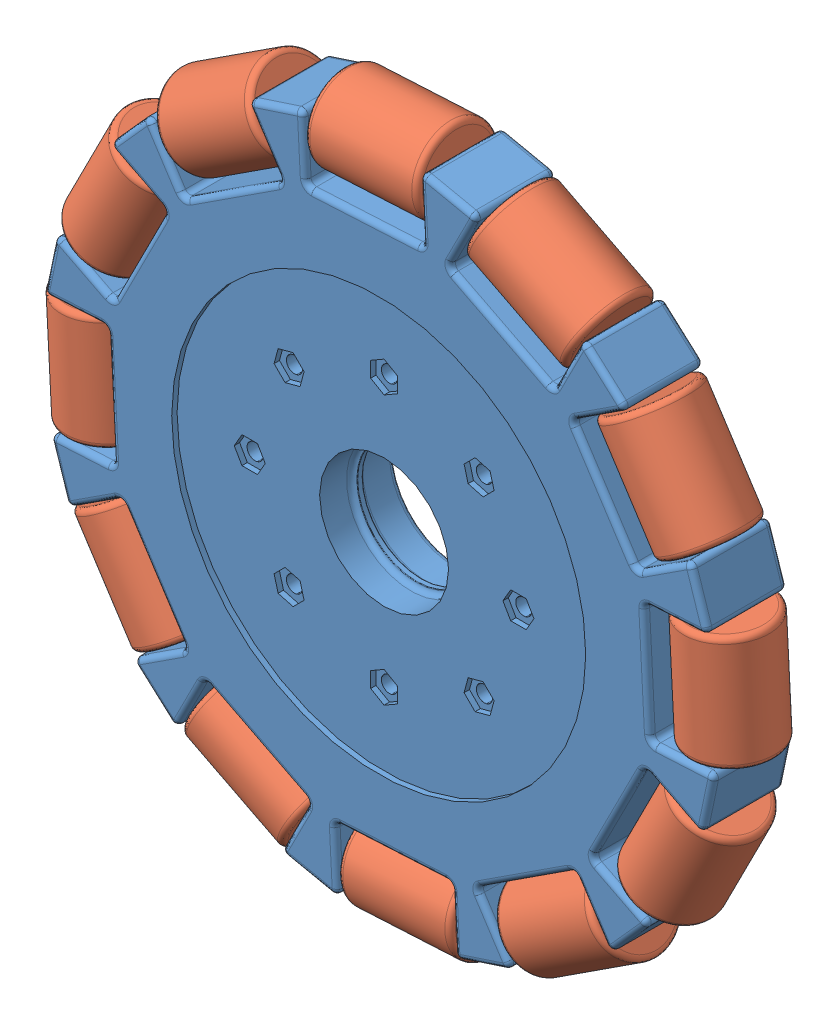
SolidWorks assembly single wheel assembly 2, configuration Default. Lengths in mm.
Overall size (136.5 135.47 21.6).
13 component instances, 2 part files, 24 mates.
Components (placement in the parent):
- basic 2-1: basic 2 [Default] at (35.8577 70.8683 90.1454) size (124.49 124.49 16)
- omni new-1: omni new [Default] at (-21.5279 57.3036 97.6454) x (-0.815938 -0.04339 -0.576509) z (-0.053103 0.998589 0) size (15.5 15.5 21)
- omni new-2: omni new [Default] at (52.8031 127.3481 97.6454) x (-0.161602 -0.317764 0.934297) z (0.891355 -0.453306 0) size (15.5 15.5 21)
- omni new-3: omni new [Default] at (78.7727 111.3085 97.6454) x (0.32871 0.213826 -0.919907) z (0.545283 -0.838252 0) size (15.5 15.5 21)
- omni new-4: omni new [Default] at (-7.0574 30.4282 97.6454) x (0.838115 0.545194 -0.018063) z (-0.545283 0.838252 0) size (15.5 15.5 21)
- omni new-5: omni new [Default] at (-20.6221 87.8138 97.6454) x (-0.008108 0.004124 0.999959) z (0.453306 0.891355 0) size (15.5 15.5 21)
- omni new-6: omni new [Default] at (49.4224 13.4827 97.6454) x (-0.023043 0.433324 0.900943) z (-0.998589 -0.053103 0) size (15.5 15.5 21)
- omni new-7: omni new [Default] at (22.293 128.2539 97.6454) x (-0.002823 0.05308 0.998586) z (0.998589 0.053103 0) size (15.5 15.5 21)
- omni new-8: omni new [Default] at (76.2978 27.9533 97.6454) x (0.490719 -0.754373 -0.436023) z (-0.838252 -0.545283 0) size (15.5 15.5 21)
- omni new-9: omni new [Default] at (-4.5825 113.7834 97.6454) x (0.48418 -0.744321 -0.459952) z (0.838252 0.545283 0) size (15.5 15.5 21)
- omni new-10: omni new [Default] at (18.9122 14.3886 97.6454) x (0.258929 0.509143 0.82081) z (-0.891355 0.453306 0) size (15.5 15.5 21)
- omni new-11: omni new [Default] at (93.2433 84.433 97.6454) x (-0.135568 -0.007209 0.990742) z (0.053103 -0.998589 0) size (15.5 15.5 21)
- omni new-12: omni new [Default] at (92.3374 53.9229 97.6454) x (0.750582 -0.381715 -0.539371) z (-0.453306 -0.891355 0) size (15.5 15.5 21)
Mates (geometry in assembly coordinates):
- Concentric1: concentric anti-aligned: cylinder of basic 2-1 through (44.8654 129.4543 97.6454) axis (-0.998589 -0.053103 0) radius 0.5; cylinder of omni new-7 through (-8.3637 126.6237 97.6454) axis (0.998589 0.053103 0) radius 0.505
- Concentric2: concentric anti-aligned: cylinder of basic 2-1 through (14.3656 126.1091 97.6454) axis (-0.838252 -0.545283 0) radius 0.5; cylinder of omni new-9 through (-30.3169 97.0432 97.6454) axis (0.838252 0.545283 0) radius 0.505
- Concentric3: concentric anti-aligned: cylinder of basic 2-1 through (-10.3754 107.9622 97.6454) axis (-0.453306 -0.891355 0) radius 0.5; cylinder of omni new-5 through (-34.5386 60.4492 97.6454) axis (0.453306 0.891355 0) radius 0.505
- Concentric4: concentric anti-aligned: cylinder of basic 2-1 through (-22.7283 79.876 97.6454) axis (0.053103 -0.998589 0) radius 0.5; cylinder of omni new-1 through (-19.8977 26.6469 97.6454) axis (-0.053103 0.998589 0) radius 0.505
- Concentric5: concentric anti-aligned: cylinder of basic 2-1 through (-19.3831 49.3763 97.6454) axis (0.545283 -0.838252 0) radius 0.5; cylinder of omni new-4 through (9.6828 4.6938 97.6454) axis (-0.545283 0.838252 0) radius 0.505
- Concentric6: concentric anti-aligned: cylinder of basic 2-1 through (-1.2362 24.6353 97.6454) axis (0.891355 -0.453306 0) radius 0.5; cylinder of omni new-10 through (46.2768 0.4721 97.6454) axis (-0.891355 0.453306 0) radius 0.505
- Concentric7: concentric anti-aligned: cylinder of basic 2-1 through (26.8499 12.2824 97.6454) axis (0.998589 0.053103 0) radius 0.5; cylinder of omni new-6 through (80.079 15.113 97.6454) axis (-0.998589 -0.053103 0) radius 0.505
- Concentric8: concentric anti-aligned: cylinder of basic 2-1 through (72.9515 117.1014 97.6454) axis (-0.891355 0.453306 0) radius 0.5; cylinder of omni new-2 through (25.4385 141.2646 97.6454) axis (0.891355 -0.453306 0) radius 0.505
- Concentric9: concentric anti-aligned: cylinder of basic 2-1 through (91.0984 92.3604 97.6454) axis (-0.545283 0.838252 0) radius 0.5; cylinder of omni new-3 through (62.0325 137.0429 97.6454) axis (0.545283 -0.838252 0) radius 0.505
- Concentric10: concentric anti-aligned: cylinder of basic 2-1 through (94.4436 61.8606 97.6454) axis (-0.053103 0.998589 0) radius 0.5; cylinder of omni new-11 through (91.613 115.0897 97.6454) axis (0.053103 -0.998589 0) radius 0.505
- Concentric11: concentric anti-aligned: cylinder of basic 2-1 through (82.0907 33.7744 97.6454) axis (0.453306 0.891355 0) radius 0.5; cylinder of omni new-12 through (106.2539 81.2875 97.6454) axis (-0.453306 -0.891355 0) radius 0.505
- Concentric12: concentric anti-aligned: cylinder of basic 2-1 through (57.3497 15.6276 97.6454) axis (0.838252 0.545283 0) radius 0.5; cylinder of omni new-8 through (102.0322 44.6935 97.6454) axis (-0.838252 -0.545283 0) radius 0.505
- Width1: width anti-aligned: plane of omni new-7 through (22.293 128.2539 97.6454) normal (-0.998589 -0.053103 0); plane of basic 2-1 through (43.2633 129.3691 97.6454) normal (0.998589 0.053103 0); plane of omni new-7 through (22.2709 121.2179 105.1454) normal (0.998589 0.053103 0); plane of basic 2-1 through (44.0315 122.3751 105.1454) normal (-0.998589 -0.053103 0)
- Width2: width anti-aligned: plane of omni new-9 through (13.0208 125.2343 97.6454) normal (0.838252 0.545283 0); plane of basic 2-1 through (-4.5825 113.7834 97.6454) normal (-0.838252 -0.545283 0); plane of omni new-9 through (17.1831 119.5614 105.1454) normal (-0.838252 -0.545283 0); plane of basic 2-1 through (-1.0836 107.6789 105.1454) normal (0.838252 0.545283 0)
- Width3: width aligned: plane of omni new-5 through (-20.6221 87.8138 97.6454) normal (-0.453306 -0.891355 0); plane of basic 2-1 through (-11.1027 106.5322 97.6454) normal (0.453306 0.891355 0); plane of omni new-5 through (-4.6615 103.7005 105.1454) normal (-0.453306 -0.891355 0); plane of basic 2-1 through (-14.5397 84.2766 105.1454) normal (0.453306 0.891355 0)
- Width4: width anti-aligned: plane of omni new-1 through (-22.6431 78.274 97.6454) normal (-0.053103 0.998589 0); plane of basic 2-1 through (-21.5279 57.3036 97.6454) normal (0.053103 -0.998589 0); plane of omni new-1 through (-15.6491 79.0422 105.1454) normal (0.053103 -0.998589 0); plane of basic 2-1 through (-14.4919 57.2815 105.1454) normal (-0.053103 0.998589 0)
- Width5: width anti-aligned: plane of omni new-4 through (-18.5083 48.0314 97.6454) normal (-0.545283 0.838252 0); plane of basic 2-1 through (-7.0574 30.4282 97.6454) normal (0.545283 -0.838252 0); plane of omni new-4 through (-12.8354 52.1937 105.1454) normal (0.545283 -0.838252 0); plane of basic 2-1 through (-0.9529 33.9271 105.1454) normal (-0.545283 0.838252 0)
- Width6: width anti-aligned: plane of omni new-10 through (0.1938 23.908 97.6454) normal (-0.891355 0.453306 0); plane of basic 2-1 through (18.9122 14.3886 97.6454) normal (0.891355 -0.453306 0); plane of omni new-10 through (3.0255 30.3491 105.1454) normal (0.891355 -0.453306 0); plane of basic 2-1 through (22.4494 20.4709 105.1454) normal (-0.891355 0.453306 0)
- Width7: width anti-aligned: plane of omni new-6 through (28.452 12.3676 97.6454) normal (-0.998589 -0.053103 0); plane of basic 2-1 through (49.4224 13.4827 97.6454) normal (0.998589 0.053103 0); plane of omni new-6 through (27.6838 19.3616 105.1454) normal (0.998589 0.053103 0); plane of basic 2-1 through (49.4445 20.5188 105.1454) normal (-0.998589 -0.053103 0)
- Width8: width anti-aligned: plane of omni new-8 through (58.6945 16.5024 97.6454) normal (-0.838252 -0.545283 0); plane of basic 2-1 through (76.2978 27.9533 97.6454) normal (0.838252 0.545283 0); plane of omni new-8 through (54.5323 22.1753 105.1454) normal (0.838252 0.545283 0); plane of basic 2-1 through (72.7989 34.0577 105.1454) normal (-0.838252 -0.545283 0)
- Width9: width anti-aligned: plane of omni new-12 through (82.818 35.2045 97.6454) normal (-0.453306 -0.891355 0); plane of basic 2-1 through (92.3374 53.9229 97.6454) normal (0.453306 0.891355 0); plane of omni new-12 through (76.3769 38.0362 105.1454) normal (0.453306 0.891355 0); plane of basic 2-1 through (86.255 57.4601 105.1454) normal (-0.453306 -0.891355 0)
- Width10: width anti-aligned: plane of omni new-11 through (94.3584 63.4627 97.6454) normal (0.053103 -0.998589 0); plane of basic 2-1 through (93.2433 84.433 97.6454) normal (-0.053103 0.998589 0); plane of omni new-11 through (87.3644 62.6945 105.1454) normal (-0.053103 0.998589 0); plane of basic 2-1 through (86.2072 84.4551 105.1454) normal (0.053103 -0.998589 0)
- Width11: width aligned: plane of omni new-3 through (90.2236 93.7052 97.6454) normal (0.545283 -0.838252 0); plane of basic 2-1 through (78.7727 111.3085 97.6454) normal (-0.545283 0.838252 0); plane of omni new-3 through (72.6682 107.8096 105.1454) normal (0.545283 -0.838252 0); plane of basic 2-1 through (84.5507 89.5429 105.1454) normal (-0.545283 0.838252 0)
- Width12: width anti-aligned: plane of omni new-2 through (52.8031 127.3481 97.6454) normal (-0.891355 0.453306 0); plane of basic 2-1 through (71.5215 117.8286 97.6454) normal (0.891355 -0.453306 0); plane of omni new-2 through (49.2659 121.2657 105.1454) normal (0.891355 -0.453306 0); plane of basic 2-1 through (68.6898 111.3875 105.1454) normal (-0.891355 0.453306 0)
